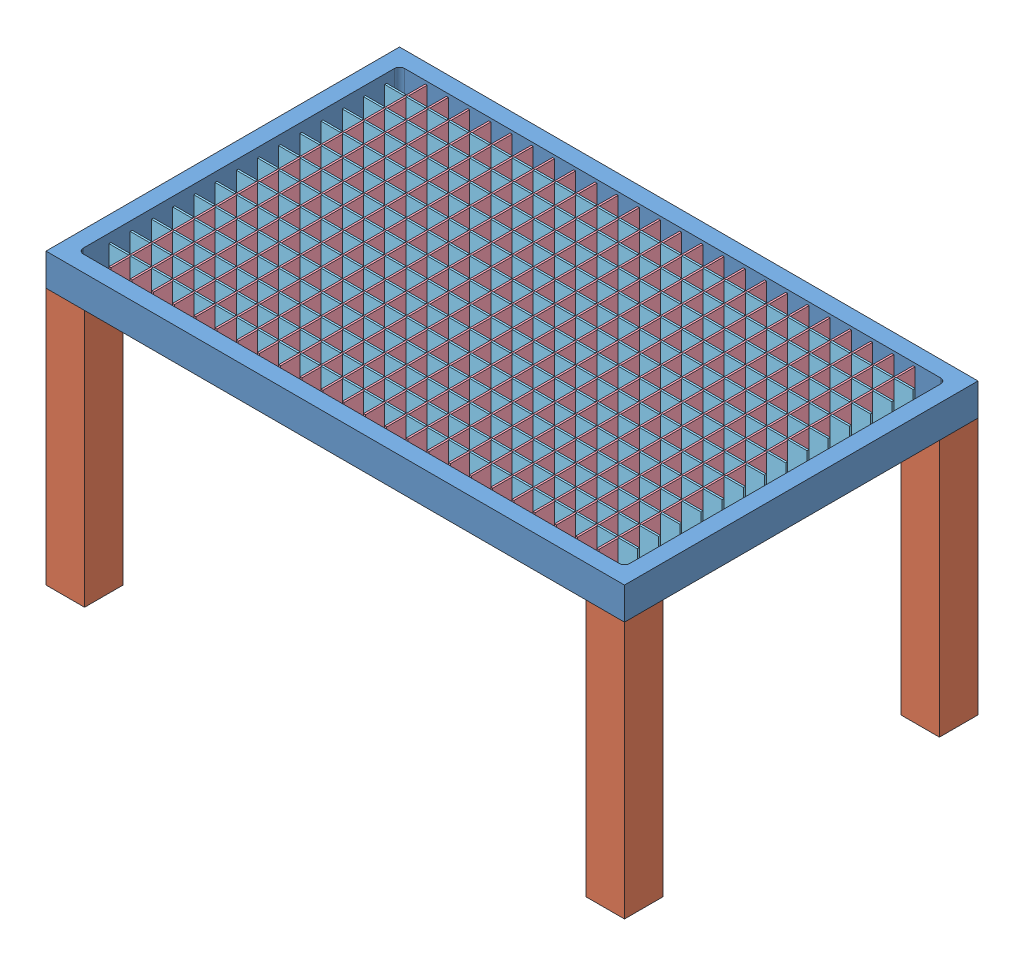
SolidWorks assembly groovegrid_lack_large, configuration Standard. Lengths in mm.
Overall size (900 450 550).
60 component instances, 7 part files, 21 mates.
Components (placement in the parent):
- groovegrid_lack_table_large-1: groovegrid_lack_table_large [Standard] at origin size (900 50 550)
- groovegrid_lack_foot_large-1: groovegrid_lack_foot_large [Standard] at (-420 -400 245) size (60 400 60)
- groovegrid_lack_foot_large-2: groovegrid_lack_foot_large [Standard] at (-420 -400 -245) size (60 400 60)
- groovegrid_lack_foot_large-3: groovegrid_lack_foot_large [Standard] at (420 -400 245) x (-1 0 0) z (0 0 -1) size (60 400 60)
- groovegrid_lack_foot_large-4: groovegrid_lack_foot_large [Standard] at (420 -400 -245) x (-1 0 0) z (0 0 -1) size (60 400 60)
- groovegrid_lack_led_large-1: groovegrid_lack_led_large [Standard] at (0 3 -231) size (825 2.2 10)
- groovegrid_lack_led_large-2: groovegrid_lack_led_large [Standard] at (0 3 -198) size (825 2.2 10)
- groovegrid_lack_led_large-3: groovegrid_lack_led_large [Standard] at (0 3 -165) size (825 2.2 10)
- groovegrid_lack_led_large-4: groovegrid_lack_led_large [Standard] at (0 3 -132) size (825 2.2 10)
- groovegrid_lack_led_large-5: groovegrid_lack_led_large [Standard] at (0 3 -99) size (825 2.2 10)
- groovegrid_lack_led_large-6: groovegrid_lack_led_large [Standard] at (0 3 -66) size (825 2.2 10)
- groovegrid_lack_led_large-7: groovegrid_lack_led_large [Standard] at (0 3 -33) size (825 2.2 10)
- groovegrid_lack_led_large-8: groovegrid_lack_led_large [Standard] at (0 3 0) size (825 2.2 10)
- groovegrid_lack_led_large-9: groovegrid_lack_led_large [Standard] at (0 3 33) size (825 2.2 10)
- groovegrid_lack_led_large-10: groovegrid_lack_led_large [Standard] at (0 3 66) size (825 2.2 10)
- groovegrid_lack_led_large-11: groovegrid_lack_led_large [Standard] at (0 3 99) size (825 2.2 10)
- groovegrid_lack_led_large-12: groovegrid_lack_led_large [Standard] at (0 3 132) size (825 2.2 10)
- groovegrid_lack_led_large-13: groovegrid_lack_led_large [Standard] at (0 3 165) size (825 2.2 10)
- groovegrid_lack_led_large-14: groovegrid_lack_led_large [Standard] at (0 3 198) size (825 2.2 10)
- groovegrid_lack_led_large-15: groovegrid_lack_led_large [Standard] at (0 3 231) size (825 2.2 10)
- groovegrid_lack_sep1_large-1: groovegrid_lack_sep1_large [Standard] at (-378 26.5 0) x (0 0 1) z (-1 0 0) size (492 45 3)
- groovegrid_lack_sep1_large-2: groovegrid_lack_sep1_large [Standard] at (-345 26.5 0) x (0 0 1) z (-1 0 0) size (492 45 3)
- groovegrid_lack_sep1_large-3: groovegrid_lack_sep1_large [Standard] at (-312 26.5 0) x (0 0 1) z (-1 0 0) size (492 45 3)
- groovegrid_lack_sep1_large-4: groovegrid_lack_sep1_large [Standard] at (-279 26.5 0) x (0 0 1) z (-1 0 0) size (492 45 3)
- groovegrid_lack_sep1_large-5: groovegrid_lack_sep1_large [Standard] at (-246 26.5 0) x (0 0 1) z (-1 0 0) size (492 45 3)
- groovegrid_lack_sep1_large-6: groovegrid_lack_sep1_large [Standard] at (-213 26.5 0) x (0 0 1) z (-1 0 0) size (492 45 3)
- groovegrid_lack_sep1_large-7: groovegrid_lack_sep1_large [Standard] at (-180 26.5 0) x (0 0 1) z (-1 0 0) size (492 45 3)
- groovegrid_lack_sep1_large-8: groovegrid_lack_sep1_large [Standard] at (-147 26.5 0) x (0 0 1) z (-1 0 0) size (492 45 3)
- groovegrid_lack_sep1_large-9: groovegrid_lack_sep1_large [Standard] at (-114 26.5 0) x (0 0 1) z (-1 0 0) size (492 45 3)
- groovegrid_lack_sep1_large-10: groovegrid_lack_sep1_large [Standard] at (-81 26.5 0) x (0 0 1) z (-1 0 0) size (492 45 3)
- groovegrid_lack_sep1_large-11: groovegrid_lack_sep1_large [Standard] at (-48 26.5 0) x (0 0 1) z (-1 0 0) size (492 45 3)
- groovegrid_lack_sep1_large-12: groovegrid_lack_sep1_large [Standard] at (-15 26.5 0) x (0 0 1) z (-1 0 0) size (492 45 3)
- groovegrid_lack_sep1_large-13: groovegrid_lack_sep1_large [Standard] at (18 26.5 0) x (0 0 1) z (-1 0 0) size (492 45 3)
- groovegrid_lack_sep1_large-14: groovegrid_lack_sep1_large [Standard] at (51 26.5 0) x (0 0 1) z (-1 0 0) size (492 45 3)
- groovegrid_lack_sep1_large-15: groovegrid_lack_sep1_large [Standard] at (84 26.5 0) x (0 0 1) z (-1 0 0) size (492 45 3)
- groovegrid_lack_sep1_large-16: groovegrid_lack_sep1_large [Standard] at (117 26.5 0) x (0 0 1) z (-1 0 0) size (492 45 3)
- groovegrid_lack_sep1_large-17: groovegrid_lack_sep1_large [Standard] at (150 26.5 0) x (0 0 1) z (-1 0 0) size (492 45 3)
- groovegrid_lack_sep1_large-18: groovegrid_lack_sep1_large [Standard] at (183 26.5 0) x (0 0 1) z (-1 0 0) size (492 45 3)
- groovegrid_lack_sep1_large-19: groovegrid_lack_sep1_large [Standard] at (216 26.5 0) x (0 0 1) z (-1 0 0) size (492 45 3)
- groovegrid_lack_sep1_large-20: groovegrid_lack_sep1_large [Standard] at (249 26.5 0) x (0 0 1) z (-1 0 0) size (492 45 3)
- groovegrid_lack_sep1_large-21: groovegrid_lack_sep1_large [Standard] at (282 26.5 0) x (0 0 1) z (-1 0 0) size (492 45 3)
- groovegrid_lack_sep1_large-22: groovegrid_lack_sep1_large [Standard] at (315 26.5 0) x (0 0 1) z (-1 0 0) size (492 45 3)
- groovegrid_lack_sep1_large-23: groovegrid_lack_sep1_large [Standard] at (348 26.5 0) x (0 0 1) z (-1 0 0) size (492 45 3)
- groovegrid_lack_sep1_large-24: groovegrid_lack_sep1_large [Standard] at (381 26.5 0) x (0 0 1) z (-1 0 0) size (492 45 3)
- groovegrid_lack_sep2_large-1: groovegrid_lack_sep2_large [Standard] at (0 26.5 -213) x (1 0 0) z (0 0 -1) size (822 47 3)
- groovegrid_lack_sep2_large-2: groovegrid_lack_sep2_large [Standard] at (0 26.5 -180) x (1 0 0) z (0 0 -1) size (822 47 3)
- groovegrid_lack_sep2_large-3: groovegrid_lack_sep2_large [Standard] at (0 26.5 -147) x (1 0 0) z (0 0 -1) size (822 47 3)
- groovegrid_lack_sep2_large-4: groovegrid_lack_sep2_large [Standard] at (0 26.5 -114) x (1 0 0) z (0 0 -1) size (822 47 3)
- groovegrid_lack_sep2_large-5: groovegrid_lack_sep2_large [Standard] at (0 26.5 -81) x (1 0 0) z (0 0 -1) size (822 47 3)
- groovegrid_lack_sep2_large-6: groovegrid_lack_sep2_large [Standard] at (0 26.5 -48) x (1 0 0) z (0 0 -1) size (822 47 3)
- groovegrid_lack_sep2_large-7: groovegrid_lack_sep2_large [Standard] at (0 26.5 -15) x (1 0 0) z (0 0 -1) size (822 47 3)
- groovegrid_lack_sep2_large-8: groovegrid_lack_sep2_large [Standard] at (0 26.5 18) x (1 0 0) z (0 0 -1) size (822 47 3)
- groovegrid_lack_sep2_large-9: groovegrid_lack_sep2_large [Standard] at (0 26.5 51) x (1 0 0) z (0 0 -1) size (822 47 3)
- groovegrid_lack_sep2_large-10: groovegrid_lack_sep2_large [Standard] at (0 26.5 84) x (1 0 0) z (0 0 -1) size (822 47 3)
- groovegrid_lack_sep2_large-11: groovegrid_lack_sep2_large [Standard] at (0 26.5 117) x (1 0 0) z (0 0 -1) size (822 47 3)
- groovegrid_lack_sep2_large-12: groovegrid_lack_sep2_large [Standard] at (0 26.5 150) x (1 0 0) z (0 0 -1) size (822 47 3)
- groovegrid_lack_sep2_large-13: groovegrid_lack_sep2_large [Standard] at (0 26.5 183) x (1 0 0) z (0 0 -1) size (822 47 3)
- groovegrid_lack_sep2_large-14: groovegrid_lack_sep2_large [Standard] at (0 26.5 216) x (1 0 0) z (0 0 -1) size (822 47 3)
- groovegrid_lack_glass_large-2: groovegrid_lack_glass_large [Standard] at (0 50 0) size (900 6 550) (hidden)
- groovegrid_lack_pcb_large-1: groovegrid_lack_pcb_large [Standard] at (424 21 -122.6482) x (0 0 1) z (0 -1 0) size (190 1.6 30)
Mates (geometry in assembly coordinates):
- Coincident3: coincident: point of groovegrid_lack_table_large-1; point of groovegrid_lack_foot_large-1
- Coincident4: coincident: plane of groovegrid_lack_table_large-1 through (0 3 0) normal (0 1 0); plane of groovegrid_lack_led_large-1 through (0 3 -231) normal (0 -1 0)
- Parallel1: parallel: line of groovegrid_lack_table_large-1 through (-417 3 -250) axis (1 0 0); line of groovegrid_lack_led_large-1 through (412.5 3 -236) axis (-1 0 0)
- Coincident6: coincident: moEndPointRef_w of groovegrid_lack_led_large-1; plane of assembly
- Distance1: distance = 14 mm: line of groovegrid_lack_table_large-1 through (-417 3 -250) axis (1 0 0); line of groovegrid_lack_led_large-1 through (412.5 3 -236) axis (-1 0 0)
- Parallel3: parallel: plane of groovegrid_lack_sep1_large-1 through (-381 26.5 0) normal (-1 0 0); plane of assembly through (0 0 0) normal (1 0 0)
- Coincident12: coincident: moEndPointRef_w of groovegrid_lack_sep1_large-1; plane of assembly
- Coincident14: coincident: moEndPointRef_w of groovegrid_lack_sep2_large-1; plane of assembly
- Coincident15: coincident: plane of groovegrid_lack_table_large-1 through (0 3 0) normal (0 1 0); plane of groovegrid_lack_sep2_large-1 through (-411 3 -216) normal (0 -1 0)
- Parallel4: parallel: line of groovegrid_lack_sep2_large-1 through (411 3 -213) axis (-1 0 0); plane of assembly
- Distance3: distance = 30 mm: line of groovegrid_lack_sep1_large-17 through (147 49 -246) axis (0 -1 0); line of groovegrid_lack_sep2_large-1 through (147 50 -216) axis (0 -1 0)
- Coincident20: coincident: plane of groovegrid_lack_led_large-1 through (0 4 -231) normal (0 1 0); plane of groovegrid_lack_sep1_large-1 through (-381 4 -246) normal (0 -1 0)
- Coincident21: coincident: moEndPointRef_w of groovegrid_lack_glass_large-2; plane of assembly
- Coincident22: coincident: moEndPointRef_w of groovegrid_lack_glass_large-2; plane of assembly
- Parallel7: parallel: line of groovegrid_lack_table_large-1 through (-417 50 -250) axis (1 0 0); line of groovegrid_lack_glass_large-2 through (450 50 -275) axis (-1 0 0)
- Parallel8: parallel: line of groovegrid_lack_table_large-1 through (425 50 242) axis (0 0 -1); line of groovegrid_lack_glass_large-2 through (450 50 275) axis (0 0 -1)
- Coincident25: coincident: plane of groovegrid_lack_glass_large-2 through (0 50 0) normal (0 -1 0); plane of groovegrid_lack_table_large-1 through (0 50 0) normal (0 1 0)
- Distance4: distance = 1 mm: plane of groovegrid_lack_pcb_large-1 through (424 21 -122.6482) normal (1 0 0); plane of groovegrid_lack_table_large-1 through (425 3 250) normal (-1 0 0)
- Parallel9: parallel: line of groovegrid_lack_table_large-1 through (425 50 242) axis (0 0 -1); line of groovegrid_lack_pcb_large-1 through (424 36 -27.6482) axis (0 0 -1)
- Distance6: distance = 3 mm: plane of groovegrid_lack_pcb_large-1 through (422.4 6 -217.6482) normal (0 -1 0); plane of groovegrid_lack_table_large-1 through (0 3 0) normal (0 1 0)
- Coincident26: coincident: plane of groovegrid_lack_sep1_large-1 through (-381 26.5 0) normal (-1 0 0); plane of groovegrid_lack_sep2_large-4 through (-381 50 -114) normal (1 0 0)
